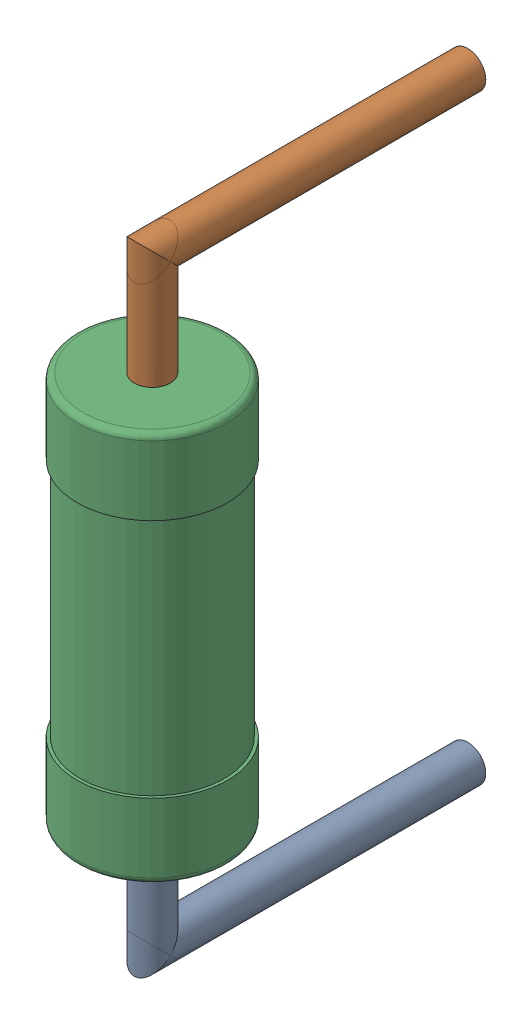
SolidWorks assembly R2.step, configuration Default. Lengths in mm.
Overall size (2.5 10.6 6.5).
3 component instances, 3 part files, 0 mates.
Components (placement in the parent):
- Res_Vishay_BC_Components_MRS25000C1101FCT00_eec.step-1: Res_Vishay_BC_Components_MRS25000C1101FCT00_eec.step [Default] at (24.384 59.436 0) x (0 1 0) z (0 0 1) size (2.05 0.6 5.55)
- Res_Vishay_BC_Components_MRS25000C1101FCT00_eec-2.step-1: Res_Vishay_BC_Components_MRS25000C1101FCT00_eec-2.step [Default] at (24.384 59.436 0) x (0 1 0) z (0 0 1) size (2.05 0.6 5.55)
- Res_Vishay_BC_Components_MRS25000C1101FCT00_eec-3.step-1: Res_Vishay_BC_Components_MRS25000C1101FCT00_eec-3.step [Default] at (24.384 59.436 0) x (0 1 0) z (0 0 1) size (6.5 2.5 2.5)
